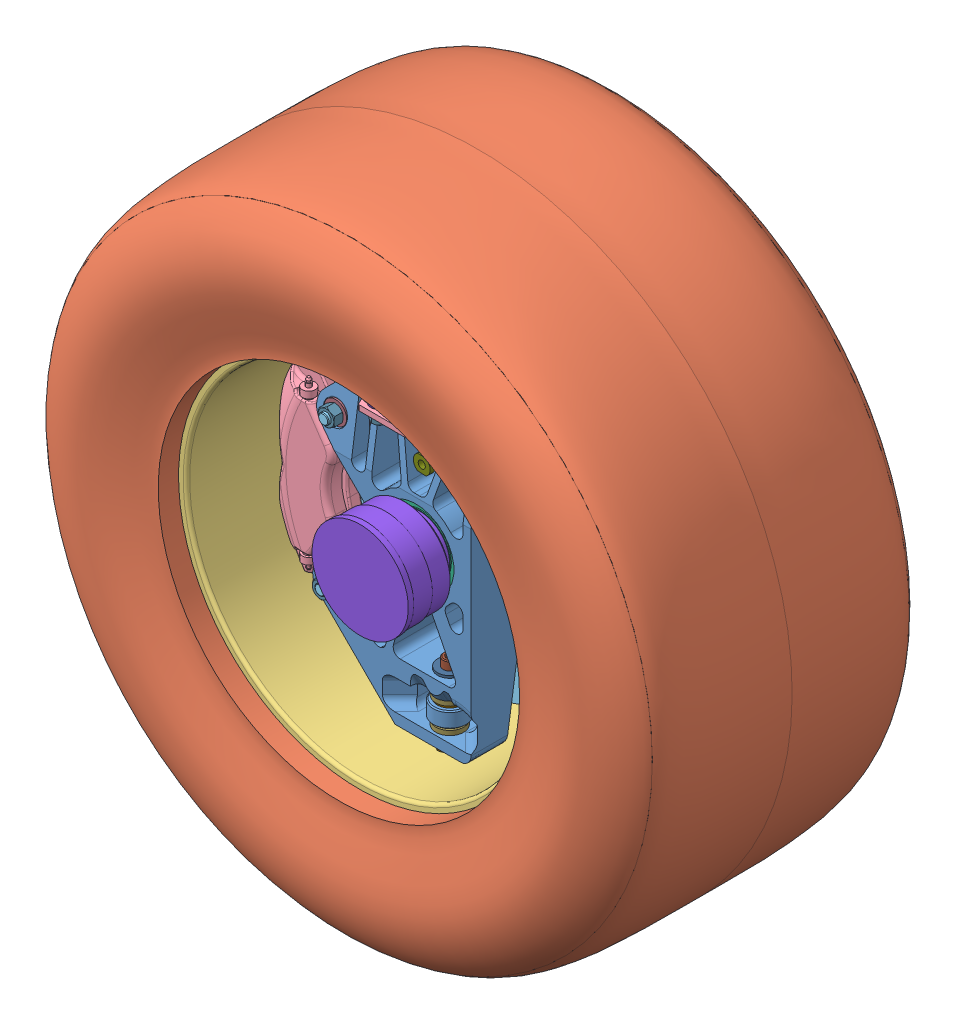
SolidWorks assembly CornerLR_Complete, configuration Default. Lengths in mm.
Overall size (801.05 801.05 310.41).
79 component instances, 32 part files, 138 mates.
Components (placement in the parent):
- UprighntLFLugBillet-2: UprighntLFLugBillet [Final Part] at origin size (558 599.44 88.5)
- TireRear-2: TireRear [Default] at (0 0 8.825) x (-0.562655 -0.826691 0) z (0 0 1) size (576.57 576.57 310.41)
- Wheel9J13-2: Wheel9J13 [Default] at (0 0 -6.73) x (-0.380341 0.924846 0) z (0 0 -1) size (367.66 367.66 243.31)
- SteeringArm-2: SteeringArm [Finished Part Left] at (-42.5 126.5 51.625) size (110 32.34 39)
- BrakeDiscWilwood160-10021-1: BrakeDiscWilwood160-10021 [Default] at (0 0 12.675) x (0.133038 0.991111 0) z (0 0 1) size (266.7 266.7 9.12)
- BearingWheelCivicFront-1: BearingWheelCivicFront [Default] at (0 0 21.82) x (-0.973136 -0.230231 0) z (0 0 1) size (73.1 73.1 55.34)
- WheelNut-1: WheelNut [Default] at (-0.0272 -0.0421 -52.1943) x (0 0 -1) z (0.976774 0.21427 0) size (26.97 65 74.13)
- WheelDrivePin-1: WheelDrivePin [Default] at (-44.0227 -18.1043 -6.38) x (-0.73494 0.678133 0) z (0.678133 0.73494 0) size (19.05 44.86 17)
- WheelDrivePin-2: WheelDrivePin [Default] at (44.0227 18.1043 -6.38) x (0.925266 0.379318 0) z (0.379318 -0.925266 0) size (19.05 44.86 17)
- WheelDrivePin-3: WheelDrivePin [Default] at (18.1043 -44.0227 -6.38) x (0.256263 -0.966607 0) z (-0.966607 -0.256263 0) size (19.05 44.86 17)
- WheelDrivePin-4: WheelDrivePin [Default] at (-18.1043 44.0227 -6.38) x (0.572125 0.820166 0) z (0.820166 -0.572125 0) size (19.05 44.86 17)
- Pin625-1: Pin625 [Default] at (15.843 -95 50.4139) x (-0.837169 0 -0.546944) z (0.546944 0 -0.837169) size (25.4 58 20)
- Flat Washer Type A Wide_AI-1: Flat Washer Type A Wide_AI [Preferred Wide FW 0.3125] at (15.843 -95 50.4139) x (0 -1 0) z (0.546944 0 -0.837169) size (2.11 22.23 22.23)
- Socket Head Cap Screw_AI-1: Socket Head Cap Screw_AI [HX-SHCS 0.3125-24x0.4375x0.4375-N] at (15.843 -84.9543 50.4139) x (0 -1 0) z (0.546944 0 -0.837169) size (19.05 11.91 11.91)
- Basic Internal Retaining Ring_am-1: Basic Internal Retaining Ring_am [B27.7M - 3BM1-72] at (0 0 21.667) x (0.982503 0.186249 0) z (0 0 1) size (76.5 74.92 2.4)
- Flat Washer Type A Narrow_AI-5: Flat Washer Type A Narrow_AI [Preferred Narrow FW 0.3125] at (-29.5 126.5 62.625) x (0 0 -1) z (0.926229 -0.376962 0) size (1.65 17.48 17.48)
- Flat Washer Type A Narrow_AI-6: Flat Washer Type A Narrow_AI [Preferred Narrow FW 0.3125] at (32.5 126.5 62.625) x (0 0 -1) z (0.352455 0.935829 0) size (1.65 17.48 17.48)
- Flat Washer Type A Narrow_AI-7: Flat Washer Type A Narrow_AI [Preferred Narrow FW 0.3125] at (32.5 126.5 40.625) x (0 0 1) z (-1 0 0) size (1.65 17.48 17.48)
- Flat Washer Type A Narrow_AI-8: Flat Washer Type A Narrow_AI [Preferred Narrow FW 0.3125] at (-29.5 126.5 40.625) x (0 0 1) z (-1 0 0) size (1.65 17.48 17.48)
- Socket Head Cap Screw_AI-2: Socket Head Cap Screw_AI [HX-SHCS 0.3125-24x1.25x1.25-N] at (-29.5 126.5 72.2135) x (0 0 -1) z (1 0 0) size (39.69 11.91 11.91)
- Socket Head Cap Screw_AI-3: Socket Head Cap Screw_AI [HX-SHCS 0.3125-24x1.25x1.25-N] at (32.5 126.5 72.2135) x (0 0 -1) z (1 0 0) size (39.69 11.91 11.91)
- Hex Nut_AI-7: Hex Nut_AI [HNUT 0.3125-24-D-N] at (32.5 126.5 32.0398) x (0.923728 0.383049 0) z (0 0 -1) size (12.7 14.66 6.93)
- Hex Nut_AI-8: Hex Nut_AI [HNUT 0.3125-24-D-N] at (-29.5 126.5 32.0398) x (0.923728 0.383049 0) z (0 0 -1) size (12.7 14.66 6.93)
- RodEnd8mmFem-2: RodEnd8mmFem [Default] at (59.9 121.5 82.525) x (-0.999058 0 -0.043388) z (0 -1 0) size (22 47 22.2) (flexible)
  - RodEndBall8mm-1: RodEndBall8mm [Default] at origin size (15.88 15.88 22.2)
  - RodEndRace8mmFem-1: RodEndRace8mmFem [Default] at origin size (22 47 14)
- bush437x500x345-1: bush437x500x345 [Default] at (-16.1 133.7499 82.525) x (0.999868 0 -0.016231) z (0.016231 0 0.999868) size (16 8.75 16)
- bush437x500x345-2: bush437x500x345 [Default] at (-16.1 119.2501 82.525) x (-0.439949 0 -0.898023) z (-0.898023 0 0.439949) size (16 8.75 16)
- BearingSpherical625-1: BearingSpherical625 [Default] at (15.843 -125.485 50.4139) x (0.913358 0 -0.407157) z (0.407157 0 0.913358) size (30.79 22.58 32.6) (flexible)
  - SphericalBearingBall625-1: SphericalBearingBall625 [Default] x (1 0 0) z (0 -1 0) size (26.97 32.6 22.58)
  - SphericalBeaingRace625-1: SphericalBeaingRace625 [Default] x (0.999776 0 -0.021151) z (0 -1 0) size (30.16 30.16 14.4)
- SphericalBearing437in-1: SphericalBearing437in [Default] at (-16.1 126.5 82.525) x (0.999488 0 -0.032002) z (0 -1 0) size (23.81 23.81 14.27) (flexible)
  - SphericalBearing437Race-1: SphericalBearing437Race [Default] at origin size (23.81 23.81 11.23)
  - SphericalBearing437Ball-1: SphericalBearing437Ball [Default] at origin size (19.84 19.84 14.27)
- CaliperWilwood120-6818-1: CaliperWilwood120-6818 [Default] at (-77.1694 0 31.975) x (0 1 0) z (0 0 1) size (180.93 86.45 102.63)
- Flat Washer Type A Narrow_AI-1: Flat Washer Type A Narrow_AI [Preferred Narrow FW 0.375] at (-77.1694 66.7 27.025) x (0 0 1) z (-1 0 0) size (1.65 20.62 20.62)
- Flat Washer Type A Narrow_AI-2: Flat Washer Type A Narrow_AI [Preferred Narrow FW 0.375] at (-77.1694 -66.7 27.025) x (0 0 1) z (-1 0 0) size (1.65 20.62 20.62)
- Flat Washer Type A Narrow_AI-3: Flat Washer Type A Narrow_AI [Preferred Narrow FW 0.375] at (-77.1694 -66.7 65.625) x (0 0 -1) z (1 0 0) size (1.65 20.62 20.62)
- Flat Washer Type A Narrow_AI-4: Flat Washer Type A Narrow_AI [Preferred Narrow FW 0.375] at (-77.1694 66.7 60.225) x (0 0 -1) z (1 0 0) size (1.65 20.62 20.62)
- Hex Bolt_AI-1: Hex Bolt_AI [HBOLT 0.375-24x1.875x1-N] at (-77.1694 66.7 18.5668) x (0 0 1) z (-1 0 0) size (54.43 16.48 14.27)
- Hex Bolt_AI-2: Hex Bolt_AI [HBOLT 0.375-24x2x1-N] at (-77.1694 -66.7 18.5668) x (0 0 1) z (-1 0 0) size (57.61 16.48 14.27)
- Hex Nut_AI-1: Hex Nut_AI [HNUT 0.3750-24-D-N] at (-77.1694 66.7 70.4358) size (14.27 16.48 8.56)
- Hex Nut_AI-2: Hex Nut_AI [HNUT 0.3750-24-D-N] at (-77.1694 -66.7 75.8358) x (0.99983 0.018462 0) z (0 0 1) size (14.27 16.48 8.56)
- WheelHubHondaCivic-1: WheelHubHondaCivic [Default] at (0 0 21.82) x (0.999997 -0.002534 0) z (0 0 -1) size (120.8 125.54 59.3)
- AdapterWheelHubToDisc-1: AdapterWheelHubToDisc [Finished Part] at (0 0 5.62) x (0.924846 0.380341 0) z (0 0 1) size (138.98 157.7 6)
- CVjointCivicOuter-1: CVjointCivicOuter [Default] at (0 0 116.42) x (0 0 -1) z (0.202887 0.979202 0) size (134.6 88 88)
- NutHondaCivWhlBrngRet-1: NutHondaCivWhlBrngRet [Default] at (0 0 -2.08) x (-0.872533 0.488555 0) z (0 0 -1) size (36.6 36.6 19.8)
- AxleStub-1: AxleStub [Default] at (0 0 3.92) x (0.822864 -0.568239 0) z (0 0 1) size (56.9 57.5 80.26)
- SpacerWheelHubToWheel-1: SpacerWheelHubToWheel [Default] at (0 0 -6.73) x (0.924846 0.380341 0) z (0 0 1) size (117.5 117.5 6.35)
- Bush16x19x4-1: Bush16x19x4 [Upper Bushing] at (15.843 -111.86 50.4139) x (-1 0 0) z (0 0 1) size (25.4 20.96 25.4)
- Bush16x19x4-2: Bush16x19x4 [Lower Bushing] at (15.843 -139.2 50.4139) x (0.837169 0 -0.546944) z (0.546944 0 0.837169) size (25.4 13.9 25.4)
- Flat Washer Type A Narrow_AI-29: Flat Washer Type A Narrow_AI [Preferred Narrow FW 0.3125] at (-16.1 142.5 82.525) x (0 -1 0) z (0 0 1) size (1.65 17.48 17.48)
- Flat Washer Type A Narrow_AI-30: Flat Washer Type A Narrow_AI [Preferred Narrow FW 0.3125] at (-16.1 110.5 82.525) x (0 1 0) z (0 0 1) size (1.65 17.48 17.48)
- Hex Nut_AI-22: Hex Nut_AI [HNUT 0.3125-24-D-N] at (-16.1 101.9148 82.525) x (1 0 0) z (0 -1 0) size (12.7 14.66 6.93)
- Flat Washer Type A Narrow_AI-31: Flat Washer Type A Narrow_AI [Preferred Narrow FW 0.3125] at (59.9 110.5 82.525) x (0 1 0) z (0 0 1) size (1.65 17.48 17.48)
- Flat Washer Type A Narrow_AI-32: Flat Washer Type A Narrow_AI [Preferred Narrow FW 0.3125] at (59.9 132.0562 82.525) x (0 -1 0) z (0 0 1) size (1.65 17.48 17.48)
- Hex Nut_AI-23: Hex Nut_AI [HNUT 0.3125-24-D-N] at (59.9 101.9148 82.525) x (1 0 0) z (0 -1 0) size (12.7 14.66 6.93)
- Hex Bolt_AI-9: Hex Bolt_AI [HBOLT 0.3125-24x1.75x1.75-N] at (-16.1 150.12 82.525) x (0 -1 0) z (0 0 1) size (50.42 14.66 12.7)
- Hex Bolt_AI-10: Hex Bolt_AI [HBOLT 0.3125-24x1.25x1.25-N] at (59.9 139.6763 82.525) x (0 -1 0) z (0 0 1) size (37.72 14.66 12.7)
- StudDiscMntRear-1: StudDiscMntRear [Default] at (69.2291 -9.2927 8.23) x (0 0 -1) z (1 0 0) size (26.61 16 18)
- StudDiscMntRear-2: StudDiscMntRear [Default] at (42.6623 55.3078 8.23) x (0 0 -1) z (0.5 0.866025 0) size (26.61 16 18)
- StudDiscMntRear-3: StudDiscMntRear [Default] at (-26.5669 64.6005 8.23) x (0 0 -1) z (-0.5 0.866025 0) size (26.61 16 18)
- StudDiscMntRear-4: StudDiscMntRear [Default] at (-69.2291 9.2927 8.23) x (0 0 -1) z (-1 0 0) size (26.61 16 18)
- StudDiscMntRear-5: StudDiscMntRear [Default] at (-42.6623 -55.3078 8.23) x (0 0 -1) z (-0.5 -0.866025 0) size (26.61 16 18)
- StudDiscMntRear-6: StudDiscMntRear [Default] at (26.5669 -64.6005 8.23) x (0 0 -1) z (0.5 -0.866025 0) size (26.61 16 18)
- Flat Washer Type A Narrow_AI-33: Flat Washer Type A Narrow_AI [Preferred Narrow FW 0.3125] at (69.2291 -9.2927 -0.38) x (0 0 1) z (-1 0 0) size (1.65 17.48 17.48)
- Hex Nut_AI-25: Hex Nut_AI [HNUT 0.3125-24-D-N] at (69.2291 -9.2927 -8.9652) x (0.923728 0.383049 0) z (0 0 -1) size (12.7 14.66 6.93)
- Hex Nut_AI-26: Hex Nut_AI [HNUT 0.3125-24-D-N] at (42.6623 55.3078 -8.9652) x (0.130134 0.991496 0) z (0 0 -1) size (12.7 14.66 6.93)
- Hex Nut_AI-27: Hex Nut_AI [HNUT 0.3125-24-D-N] at (-26.5669 64.6005 -8.9652) x (-0.793594 0.608447 0) z (0 0 -1) size (12.7 14.66 6.93)
- Hex Nut_AI-28: Hex Nut_AI [HNUT 0.3125-24-D-N] at (-69.2291 9.2927 -8.9652) x (-0.923728 -0.383049 0) z (0 0 -1) size (12.7 14.66 6.93)
- Hex Nut_AI-29: Hex Nut_AI [HNUT 0.3125-24-D-N] at (-42.6623 -55.3078 -8.9652) x (-0.130134 -0.991496 0) z (0 0 -1) size (12.7 14.66 6.93)
- Hex Nut_AI-30: Hex Nut_AI [HNUT 0.3125-24-D-N] at (26.5669 -64.6005 -8.9652) x (0.793594 -0.608447 0) z (0 0 -1) size (12.7 14.66 6.93)
- Flat Washer Type A Narrow_AI-34: Flat Washer Type A Narrow_AI [Preferred Narrow FW 0.3125] at (42.6623 55.3078 -0.38) x (0 0 1) z (-0.5 -0.866025 0) size (1.65 17.48 17.48)
- Flat Washer Type A Narrow_AI-35: Flat Washer Type A Narrow_AI [Preferred Narrow FW 0.3125] at (-26.5669 64.6005 -0.38) x (0 0 1) z (0.5 -0.866025 0) size (1.65 17.48 17.48)
- Flat Washer Type A Narrow_AI-36: Flat Washer Type A Narrow_AI [Preferred Narrow FW 0.3125] at (-69.2291 9.2927 -0.38) x (0 0 1) z (1 0 0) size (1.65 17.48 17.48)
- Flat Washer Type A Narrow_AI-37: Flat Washer Type A Narrow_AI [Preferred Narrow FW 0.3125] at (-42.6623 -55.3078 -0.38) x (0 0 1) z (0.5 0.866025 0) size (1.65 17.48 17.48)
- Flat Washer Type A Narrow_AI-38: Flat Washer Type A Narrow_AI [Preferred Narrow FW 0.3125] at (26.5669 -64.6005 -0.38) x (0 0 1) z (-0.5 0.866025 0) size (1.65 17.48 17.48)
- SpacerSteeringArm3mm-5: SpacerSteeringArm3mm [Default] at (32.5 126.5 48.625) x (-1 0 0) z (0 0 1) size (26 32 3)
- SpacerSteeringArm3mm-6: SpacerSteeringArm3mm [Default] at (-29.5 126.5 48.625) size (26 32 3)
Mates (geometry in assembly coordinates):
- Concentric241: concentric: cylinder of assembly; cylinder of assembly; cylinder of Pin625-1 through (15.843 -149 50.4139) axis (0 1 0) radius 7.9375; cylinder of UprighntLFLugBillet-2 through (15.843 -149 50.4139) axis (0 1 0) radius 9.525
- Coincident211: coincident: plane of assembly; plane of assembly; plane of UprighntLFLugBillet-2 through (-99.5 -149 15.625) normal (0 -1 0); plane of Pin625-1 through (15.843 -149 50.4139) normal (0 1 0)
- Concentric251: concentric: cylinder of Flat Washer Type A Wide_AI-1 through (15.843 -60.075 50.4139) axis (0 1 0) radius 4.7625; cylinder of Pin625-1 through (15.843 -149 50.4139) axis (0 1 0) radius 7.9375
- Coincident221: coincident: plane of Pin625-1 through (15.843 -95 50.4139) normal (0 1 0); plane of Flat Washer Type A Wide_AI-1 through (11.856 -95 47.8091) normal (0 -1 0)
- Concentric261: concentric: cylinder of Flat Washer Type A Wide_AI-1 through (15.843 -60.075 50.4139) axis (0 1 0) radius 11.1125; cylinder of Socket Head Cap Screw_AI-1 through (15.843 -53.2043 50.4139) axis (0 1 0) radius 5.9538
- Coincident231: coincident: plane of Flat Washer Type A Wide_AI-1 through (6.54 -92.8918 44.336) normal (0 1 0); plane of Socket Head Cap Screw_AI-1 through (10.8587 -92.8918 47.1575) normal (0 -1 0)
- Concentric2621: concentric: cylinder of assembly; cylinder of assembly; cylinder of Basic Internal Retaining Ring_am-1 through (0 0 19.267) axis (0 0 1) radius 38.25; cylinder of UprighntLFLugBillet-2 through (0 0 61.82) axis (0 0 -1) radius 36.5
- Concentric26221: concentric: cylinder of assembly; cylinder of assembly; cylinder of SteeringArm-2 through (-29.5 126.5 93.625) axis (0 0 -1) radius 4.1021; cylinder of Flat Washer Type A Narrow_AI-5 through (-29.5 126.5 97.55) axis (0 0 1) radius 4.3688
- Coincident2321: coincident: plane of assembly; plane of SteeringArm-2 through (12.8365 126.7309 62.625) normal (0 0 1); plane of Flat Washer Type A Narrow_AI-5 through (-27.8531 130.5465 62.625) normal (0 0 -1)
- Concentric26231: concentric: cylinder of assembly; cylinder of assembly; cylinder of SteeringArm-2 through (32.5 126.5 93.625) axis (0 0 -1) radius 4.1021; cylinder of Flat Washer Type A Narrow_AI-6 through (32.5 126.5 97.55) axis (0 0 1) radius 4.3688
- Coincident2331: coincident: plane of assembly; plane of assembly; plane of SteeringArm-2 through (12.8365 126.7309 62.625) normal (0 0 1); plane of Flat Washer Type A Narrow_AI-6 through (28.4116 128.0398 62.625) normal (0 0 -1)
- Concentric26241: concentric: cylinder of assembly; cylinder of assembly; cylinder of Flat Washer Type A Narrow_AI-7 through (32.5 126.5 5.7) axis (0 0 -1) radius 4.3688; cylinder of Socket Head Cap Screw_AI-3 through (32.5 126.5 103.9635) axis (0 0 1) radius 3.9688
- Coincident2341: coincident: plane of assembly; plane of assembly; plane of UprighntLFLugBillet-2 through (38.5625 118.4375 40.625) normal (0 0 -1); plane of Flat Washer Type A Narrow_AI-7 through (32.5 130.8688 40.625) normal (0 0 1)
- Concentric26251: concentric: cylinder of assembly; cylinder of assembly; cylinder of Flat Washer Type A Narrow_AI-8 through (-29.5 126.5 5.7) axis (0 0 -1) radius 4.3688; cylinder of Socket Head Cap Screw_AI-2 through (-29.5 126.5 103.9635) axis (0 0 1) radius 3.9688
- Coincident2351: coincident: plane of assembly; plane of assembly; plane of UprighntLFLugBillet-2 through (38.5625 118.4375 40.625) normal (0 0 -1); plane of Flat Washer Type A Narrow_AI-8 through (-29.5 130.8688 40.625) normal (0 0 1)
- Concentric26261: concentric: cylinder of assembly; cylinder of assembly; cylinder of SteeringArm-2 through (-29.5 126.5 93.625) axis (0 0 -1) radius 4.1021; cylinder of Socket Head Cap Screw_AI-2 through (-29.5 126.5 103.9635) axis (0 0 1) radius 5.9538
- Coincident2361: coincident: plane of assembly; plane of assembly; plane of Flat Washer Type A Narrow_AI-5 through (-26.2063 134.593 64.276) normal (0 0 1); plane of Socket Head Cap Screw_AI-2 through (-29.5 132.4538 64.276) normal (0 0 -1)
- Concentric26281: concentric: cylinder of assembly; cylinder of assembly; cylinder of SteeringArm-2 through (32.5 126.5 93.625) axis (0 0 -1) radius 4.1021; cylinder of Socket Head Cap Screw_AI-3 through (32.5 126.5 103.9635) axis (0 0 1) radius 5.9538
- Coincident2381: coincident: plane of assembly; plane of assembly; plane of Flat Washer Type A Narrow_AI-6 through (24.3231 129.5796 64.276) normal (0 0 1); plane of Socket Head Cap Screw_AI-3 through (32.5 132.4538 64.276) normal (0 0 -1)
- Concentric26291: concentric: cylinder of assembly; cylinder of assembly; cylinder of Flat Washer Type A Narrow_AI-7 through (32.5 126.5 5.7) axis (0 0 -1) radius 4.3688; cylinder of Hex Nut_AI-7 through (32.5 126.5 57.0773) axis (0 0 -1) radius 3.9688
- Coincident2391: coincident: plane of assembly; plane of assembly; plane of Flat Washer Type A Narrow_AI-7 through (32.5 135.2376 38.974) normal (0 0 -1); plane of Hex Nut_AI-7 through (35.3086 119.7269 38.974) normal (0 0 1)
- Concentric26301: concentric: cylinder of assembly; cylinder of assembly; cylinder of Flat Washer Type A Narrow_AI-8 through (-29.5 126.5 5.7) axis (0 0 -1) radius 4.3688; cylinder of Hex Nut_AI-8 through (-29.5 126.5 57.0773) axis (0 0 -1) radius 3.9688
- Coincident2401: coincident: plane of assembly; plane of assembly; plane of Flat Washer Type A Narrow_AI-8 through (-29.5 135.2376 38.974) normal (0 0 -1); plane of Hex Nut_AI-8 through (-26.6914 119.7269 38.974) normal (0 0 1)
- Coincident241: coincident: plane of assembly; plane of assembly; plane of UprighntLFLugBillet-2 through (34.0068 0 19.267) normal (0 0 1); plane of Basic Internal Retaining Ring_am-1 through (0 0 19.267) normal (0 0 -1)
- Concentric2632: concentric: cylinder of assembly; cylinder of assembly; cylinder of SteeringArm-2 through (-29.5 126.5 93.625) axis (0 0 -1) radius 4.1021; cylinder of UprighntLFLugBillet-2 through (-29.5 126.5 65.625) axis (0 0 -1) radius 4.1021
- Concentric2635: concentric: cylinder of SteeringArm-2 through (59.9 110.5 82.525) axis (0 1 0) radius 4.1021; cylinder of ? through (59.9 90.241 82.525) axis (0 -1 0) radius 4
- Coincident244: coincident: point of SteeringArm-2; point of RodEnd8mmFem-2/RodEndBall8mm-1
- Concentric2636: concentric: cylinder of assembly; cylinder of assembly; cylinder of SteeringArm-2 through (-16.1 110.5 82.525) axis (0 1 0) radius 6.35; cylinder of bush437x500x345-1 through (-16.1 137.6125 82.525) axis (0 -1 0) radius 5.5563
- Concentric2637: concentric: cylinder of assembly; cylinder of assembly; cylinder of SteeringArm-2 through (-16.1 110.5 82.525) axis (0 1 0) radius 6.35; cylinder of bush437x500x345-2 through (-16.1 115.3875 82.525) axis (0 1 0) radius 5.5563
- Coincident245: coincident: plane of assembly; plane of assembly; plane of SteeringArm-2 through (-42.5 137.6125 129.625) normal (0 -1 0); plane of bush437x500x345-1 through (-16.1 137.6125 82.525) normal (0 1 0)
- Coincident246: coincident: plane of assembly; plane of assembly; plane of SteeringArm-2 through (-42.5 115.3875 129.625) normal (0 1 0); plane of bush437x500x345-2 through (-16.1 115.3875 82.525) normal (0 -1 0)
- Distance1: distance = 6 mm: plane of assembly; plane of assembly; plane of UprighntLFLugBillet-2 through (38.5625 118.4375 48.625) normal (0 0 1); plane of SteeringArm-2 through (-42.5 142.5 54.625) normal (0 0 -1)
- Concentric26303: concentric: cylinder of assembly; cylinder of assembly; cylinder of Pin625-1 through (15.843 -149 50.4139) axis (0 1 0) radius 7.9375; cylinder of BearingSpherical625-1/SphericalBearingBall625-1 through (15.843 -115.5936 50.4139) axis (0 1 0) radius 7.94
- Coincident2402: coincident: plane of assembly; plane of assembly; plane of BearingSpherical625-1/SphericalBearingBall625-1 through (19.0758 -115.96 57.6659) normal (0 1 0); plane of Bush16x19x4-1 through (3.143 -115.96 50.4139) normal (0 -1 0)
- Concentric26310: concentric: cylinder of SteeringArm-2 through (-16.1 110.5 82.525) axis (0 1 0) radius 6.35; cylinder of ? through (-16.1 132.1134 82.525) axis (0 -1 0) radius 11.9062
- Concentric26311: concentric: sphere of SteeringArm-2; unknown of ?
- Distance4: distance = 102 mm: line of CaliperWilwood120-6818-1 through (-77.1694 66.7 31.975) axis (0 0 1); line of BearingWheelCivicFront-1 through (0 0 13.2488) axis (0 0 1)
- Distance5: distance = 102 mm: line of CaliperWilwood120-6818-1 through (-77.1694 -66.7 49.225) axis (0 0 -1); line of BearingWheelCivicFront-1 through (0 0 13.2488) axis (0 0 1)
- Parallel1: parallel: plane of assembly through (0 0 0) normal (0 0 1); plane of CaliperWilwood120-6818-1 through (-77.1694 0 31.975) normal (0 0 1); plane of assembly
- Distance6: distance = 19.3 mm: plane of assembly; plane of assembly; plane of BrakeDiscWilwood160-10021-1 through (0 0 12.675) normal (0 0 1); plane of CaliperWilwood120-6818-1 through (-77.1694 -66.7 31.975) normal (0 0 -1)
- Parallel2: parallel: plane of assembly through (0 0 0) normal (1 0 0); plane of CaliperWilwood120-6818-1 through (-77.1694 0 31.975) normal (-1 0 0); plane of assembly
- Concentric263402: concentric: cylinder of Flat Washer Type A Narrow_AI-1 through (-77.1694 66.7 -7.9) axis (0 0 -1) radius 5.1562; cylinder of Hex Bolt_AI-1 through (-77.1694 66.7 18.5668) axis (0 0 -1) radius 4.7625
- Coincident24383: coincident: plane of UprighntLFLugBillet-2 through (-77.191 66.675 27.025) normal (0 0 -1); plane of Flat Washer Type A Narrow_AI-1 through (-77.1694 71.8562 27.025) normal (0 0 1)
- Concentric263403: concentric: cylinder of Flat Washer Type A Narrow_AI-2 through (-77.1694 -66.7 -7.9) axis (0 0 -1) radius 5.1562; cylinder of Hex Bolt_AI-2 through (-77.1694 -66.7 18.5668) axis (0 0 -1) radius 4.7625
- Coincident24384: coincident: plane of UprighntLFLugBillet-2 through (-77.191 -66.675 27.025) normal (0 0 -1); plane of Flat Washer Type A Narrow_AI-2 through (-77.1694 -61.5438 27.025) normal (0 0 1)
- Coincident24385: coincident: plane of UprighntLFLugBillet-2 through (0 0 65.625) normal (0 0 1); plane of Flat Washer Type A Narrow_AI-3 through (-77.1694 -61.5438 65.625) normal (0 0 -1)
- Concentric263405: concentric: cylinder of Flat Washer Type A Narrow_AI-4 through (-77.1694 66.7 95.15) axis (0 0 1) radius 5.1562; cylinder of Hex Bolt_AI-1 through (-77.1694 66.7 18.5668) axis (0 0 -1) radius 4.7625
- Coincident24386: coincident: plane of UprighntLFLugBillet-2 through (-77.191 66.675 60.225) normal (0 0 1); plane of Flat Washer Type A Narrow_AI-4 through (-77.1694 71.8562 60.225) normal (0 0 -1)
- Coincident24387: coincident: plane of Flat Washer Type A Narrow_AI-1 through (-77.1694 77.0124 25.374) normal (0 0 -1); plane of Hex Bolt_AI-1 through (-77.1694 74.9416 25.374) normal (0 0 1)
- Coincident24388: coincident: plane of Flat Washer Type A Narrow_AI-2 through (-77.1694 -56.3876 25.374) normal (0 0 -1); plane of Hex Bolt_AI-2 through (-77.1694 -58.4584 25.374) normal (0 0 1)
- Concentric263408: concentric: cylinder of Hex Bolt_AI-1 through (-77.1694 66.7 18.5668) axis (0 0 -1) radius 4.7625; cylinder of Hex Nut_AI-1 through (-77.1694 66.7 45.3983) axis (0 0 1) radius 4.7625
- Coincident24389: coincident: plane of Flat Washer Type A Narrow_AI-4 through (-77.1694 77.0124 61.876) normal (0 0 1); plane of Hex Nut_AI-1 through (-91.4442 66.7 61.876) normal (0 0 -1)
- Concentric263409: concentric: cylinder of Hex Bolt_AI-2 through (-77.1694 -66.7 18.5668) axis (0 0 -1) radius 4.7625; cylinder of Hex Nut_AI-2 through (-77.1694 -66.7 50.7983) axis (0 0 1) radius 4.7625
- Coincident24390: coincident: plane of Flat Washer Type A Narrow_AI-3 through (-77.1694 -56.3876 67.276) normal (0 0 1); plane of Hex Nut_AI-2 through (-91.4417 -66.9635 67.276) normal (0 0 -1)
- Coincident24406: coincident: plane of assembly; plane of assembly; plane of Pin625-1 through (15.843 -149 50.4139) normal (0 1 0); plane of UprighntLFLugBillet-2 through (-99.5 -149 15.625) normal (0 -1 0)
- Concentric263423: concentric: cylinder of assembly; cylinder of assembly; cylinder of SteeringArm-2 through (-29.5 126.5 93.625) axis (0 0 1) radius 4.1021; cylinder of Flat Washer Type A Narrow_AI-5 through (-29.5 126.5 97.55) axis (0 0 1) radius 4.3688
- Coincident24409: coincident: plane of ? through (12.8365 126.7309 -60.2175) normal (0 0 -1); plane of Flat Washer Type A Narrow_AI-5 through (-27.8531 130.5465 62.625) normal (0 0 -1)
- Concentric263424: concentric: cylinder of assembly; cylinder of assembly; cylinder of SteeringArm-2 through (32.5 126.5 93.625) axis (0 0 -1) radius 4.1021; cylinder of Flat Washer Type A Narrow_AI-6 through (32.5 126.5 97.55) axis (0 0 1) radius 4.3688
- Coincident24410: coincident: plane of ? through (12.8365 126.7309 -60.2175) normal (0 0 -1); plane of Flat Washer Type A Narrow_AI-6 through (28.4116 128.0398 62.625) normal (0 0 -1)
- Concentric263425: concentric: cylinder of assembly; cylinder of assembly; cylinder of Flat Washer Type A Narrow_AI-7 through (32.5 126.5 5.7) axis (0 0 -1) radius 4.3688; cylinder of Socket Head Cap Screw_AI-3 through (32.5 126.5 103.9635) axis (0 0 1) radius 5.9538
- Coincident24411: coincident: plane of assembly; plane of assembly; plane of UprighntLFLugBillet-2 through (38.5625 118.4375 40.625) normal (0 0 -1); plane of Flat Washer Type A Narrow_AI-7 through (32.5 130.8688 40.625) normal (0 0 1)
- Concentric263427: concentric: cylinder of assembly; cylinder of assembly; cylinder of SteeringArm-2 through (-29.5 126.5 93.625) axis (0 0 1) radius 4.1021; cylinder of Socket Head Cap Screw_AI-2 through (-29.5 126.5 103.9635) axis (0 0 1) radius 5.9538
- Coincident24413: coincident: plane of assembly; plane of assembly; plane of Flat Washer Type A Narrow_AI-5 through (-26.2063 134.593 64.276) normal (0 0 1); plane of Socket Head Cap Screw_AI-2 through (-29.5 132.4538 64.276) normal (0 0 -1)
- Concentric263428: concentric: cylinder of assembly; cylinder of assembly; cylinder of SteeringArm-2 through (32.5 126.5 93.625) axis (0 0 -1) radius 4.1021; cylinder of Socket Head Cap Screw_AI-3 through (32.5 126.5 103.9635) axis (0 0 1) radius 5.9538
- Coincident24414: coincident: plane of assembly; plane of assembly; plane of Flat Washer Type A Narrow_AI-6 through (24.3231 129.5796 64.276) normal (0 0 1); plane of Socket Head Cap Screw_AI-3 through (32.5 132.4538 64.276) normal (0 0 -1)
- Coincident24415: coincident: plane of assembly; plane of assembly; plane of Flat Washer Type A Narrow_AI-7 through (32.5 135.2376 38.974) normal (0 0 -1); plane of Hex Nut_AI-7 through (35.3086 119.7269 32.0398) normal (0 0 -1)
- Concentric263430: concentric: cylinder of assembly; cylinder of assembly; cylinder of SteeringArm-2 through (32.5 126.5 93.625) axis (0 0 -1) radius 4.1021; cylinder of UprighntLFLugBillet-2 through (32.5 126.5 65.625) axis (0 0 -1) radius 4.1021
- Concentric263431: concentric: cylinder of assembly; cylinder of assembly; cylinder of SteeringArm-2 through (-16.1 110.5 82.525) axis (0 1 0) radius 6.35; cylinder of bush437x500x345-1 through (-16.1 137.6125 82.525) axis (0 -1 0) radius 5.5563
- Concentric263432: concentric: cylinder of assembly; cylinder of assembly; cylinder of SteeringArm-2 through (-16.1 110.5 82.525) axis (0 1 0) radius 6.35; cylinder of bush437x500x345-2 through (-16.1 115.3875 82.525) axis (0 1 0) radius 5.5563
- Coincident24418: coincident: plane of assembly; plane of assembly; plane of SteeringArm-2 through (-42.5 137.6125 129.625) normal (0 -1 0); plane of bush437x500x345-1 through (-16.1 137.6125 82.525) normal (0 1 0)
- Coincident24419: coincident: plane of ? through (-42.5 115.5 -129.2175) normal (0 1 0); plane of bush437x500x345-2 through (-16.1 119.2501 82.525) normal (0 1 0)
- Concentric263470: concentric: cylinder of assembly; cylinder of assembly; cylinder of BearingWheelCivicFront-1 through (0 0 61.82) axis (0 0 -1) radius 19; cylinder of WheelHubHondaCivic-1 through (0 0 21.82) axis (0 0 1) radius 19
- Concentric263471: concentric: cylinder of assembly; cylinder of assembly; cylinder of UprighntLFLugBillet-2 through (0 0 61.82) axis (0 0 -1) radius 36.5; cylinder of BearingWheelCivicFront-1 through (0 0 61.82) axis (0 0 -1) radius 36.55
- Coincident24471: coincident: plane of assembly; plane of assembly; plane of UprighntLFLugBillet-2 through (0 0 61.82) normal (0 0 -1); plane of BearingWheelCivicFront-1 through (0 0 61.82) normal (0 0 1)
- Coincident24472: coincident: plane of assembly; plane of assembly; plane of UprighntLFLugBillet-2 through (-94.191 13.875 49.225) normal (0 0 -1); plane of CaliperWilwood120-6818-1 through (-77.1694 -66.7 49.225) normal (0 0 1)
- Coincident24473: coincident: plane of assembly; plane of assembly; plane of BearingWheelCivicFront-1 through (0 0 21.82) normal (0 0 -1); plane of WheelHubHondaCivic-1 through (-0.0494 -19.4999 21.82) normal (0 0 1)
- Coincident24474: coincident: plane of assembly; plane of assembly; plane of WheelHubHondaCivic-1 through (-0.153 -60.3998 5.62) normal (0 0 -1); plane of AdapterWheelHubToDisc-1 through (-11.5624 28.1153 5.62) normal (0 0 1)
- Concentric263474: concentric: cylinder of assembly; cylinder of assembly; cylinder of WheelHubHondaCivic-1 through (0 0 21.82) axis (0 0 1) radius 14.1; cylinder of CVjointCivicOuter-1 through (0 0 276.1473) axis (0 0 1) radius 13.5
- Coincident24476: coincident: plane of assembly; plane of assembly; plane of BearingWheelCivicFront-1 through (0 0 61.82) normal (0 0 1); plane of CVjointCivicOuter-1 through (-13.2192 2.739 61.82) normal (0 0 -1)
- Concentric263480: concentric: cylinder of assembly; cylinder of assembly; cylinder of CVjointCivicOuter-1 through (0 0 276.1473) axis (0 0 1) radius 11; cylinder of NutHondaCivWhlBrngRet-1 through (0 0 -29.8385) axis (0 0 -1) radius 10.2
- Concentric263481: concentric: cylinder of assembly; cylinder of assembly; cylinder of CVjointCivicOuter-1 through (0 0 276.1473) axis (0 0 1) radius 11; cylinder of AxleStub-1 through (0 0 50.1767) axis (0 0 1) radius 10.9
- Coincident24479: coincident: plane of assembly; plane of assembly; plane of NutHondaCivWhlBrngRet-1 through (4.9833 8.8998 -2.08) normal (0 0 1); plane of AxleStub-1 through (9.7453 14.1121 -2.08) normal (0 0 -1)
- Coincident24480: coincident: plane of assembly; plane of assembly; plane of WheelHubHondaCivic-1 through (-0.0355 -14 3.92) normal (0 0 -1); plane of AxleStub-1 through (10.967 15.8813 3.92) normal (0 0 1)
- Coincident24481: coincident: plane of assembly; plane of assembly; plane of WheelDrivePin-3 through (15.6633 -34.8157 -0.38) normal (0 0 1); plane of AdapterWheelHubToDisc-1 through (-22.3451 54.3347 -0.38) normal (0 0 -1)
- Concentric263483: concentric: cylinder of assembly; cylinder of WheelDrivePin-3 through (18.1043 -44.0227 65.6665) axis (0 0 1) radius 9.525; cylinder of AdapterWheelHubToDisc-1 through (18.1043 -44.0227 -0.38) axis (0 0 1) radius 6.5481
- Concentric263484: concentric: cylinder of assembly; cylinder of assembly; cylinder of WheelDrivePin-2 through (44.0227 18.1043 65.6665) axis (0 0 1) radius 6.35; cylinder of WheelHubHondaCivic-1 through (44.0227 18.1043 5.62) axis (0 0 -1) radius 5.7544
- Coincident24482: coincident: plane of assembly; plane of assembly; plane of WheelDrivePin-2 through (35.2095 14.4912 -0.38) normal (0 0 1); plane of AdapterWheelHubToDisc-1 through (-22.3451 54.3347 -0.38) normal (0 0 -1)
- Concentric263486: concentric: cylinder of assembly; cylinder of assembly; cylinder of WheelDrivePin-4 through (-18.1043 44.0227 65.6665) axis (0 0 1) radius 6.35; cylinder of WheelHubHondaCivic-1 through (-18.1043 44.0227 5.62) axis (0 0 -1) radius 5.7544
- Coincident24483: coincident: plane of assembly; plane of assembly; plane of WheelDrivePin-4 through (-23.5537 36.2106 -0.38) normal (0 0 1); plane of AdapterWheelHubToDisc-1 through (-22.3451 54.3347 -0.38) normal (0 0 -1)
- Coincident24484: coincident: plane of assembly; plane of assembly; plane of WheelDrivePin-1 through (-37.0224 -24.5635 -0.38) normal (0 0 1); plane of AdapterWheelHubToDisc-1 through (-22.3451 54.3347 -0.38) normal (0 0 -1)
- Concentric263510: concentric: cylinder of assembly; cylinder of assembly; cylinder of Wheel9J13-2 through (0 0 -139.9944) axis (0 0 -1) radius 30; cylinder of AxleStub-1 through (0 0 50.1767) axis (0 0 1) radius 27.85
- Coincident24504: coincident: plane of assembly; plane of assembly; plane of Wheel9J13-2 through (27.7454 11.4102 -6.73) normal (0 0 1); plane of SpacerWheelHubToWheel-1 through (0 0 -6.73) normal (0 0 -1)
- Concentric263511: concentric: cylinder of assembly; cylinder of assembly; cylinder of Wheel9J13-2 through (-44.0227 -18.1043 -31.73) axis (0 0 1) radius 4.75; cylinder of WheelDrivePin-1 through (-44.0227 -18.1043 65.6665) axis (0 0 1) radius 6.6675
- Concentric263512: concentric: cylinder of assembly; cylinder of assembly; cylinder of WheelDrivePin-1 through (-44.0227 -18.1043 65.6665) axis (0 0 1) radius 6.35; cylinder of WheelHubHondaCivic-1 through (-44.0227 -18.1043 5.62) axis (0 0 -1) radius 5.7544
- Concentric263513: concentric: cylinder of assembly; cylinder of assembly; cylinder of WheelDrivePin-3 through (18.1043 -44.0227 65.6665) axis (0 0 1) radius 6.35; cylinder of WheelHubHondaCivic-1 through (18.1043 -44.0227 5.62) axis (0 0 -1) radius 5.7544
- Concentric263514: concentric: cylinder of assembly; cylinder of assembly; cylinder of AxleStub-1 through (0 0 50.1767) axis (0 0 1) radius 27.85; cylinder of SpacerWheelHubToWheel-1 through (0 0 -0.38) axis (0 0 -1) radius 34.5
- Coincident24505: coincident: plane of assembly; plane of assembly; plane of AdapterWheelHubToDisc-1 through (-22.3451 54.3347 -0.38) normal (0 0 -1); plane of SpacerWheelHubToWheel-1 through (0 0 -0.38) normal (0 0 1)
- Concentric263515: concentric: cylinder of assembly; cylinder of assembly; cylinder of AdapterWheelHubToDisc-1 through (18.1043 -44.0227 -0.38) axis (0 0 1) radius 6.5481; cylinder of SpacerWheelHubToWheel-1 through (18.1043 -44.0227 -0.38) axis (0 0 -1) radius 9.55
- Concentric263516: concentric: cylinder of assembly; cylinder of assembly; cylinder of Pin625-1 through (15.843 -149 50.4139) axis (0 1 0) radius 7.9375; cylinder of Bush16x19x4-1 through (15.843 -147.6258 50.4139) axis (0 -1 0) radius 7.9375
- Coincident24506: coincident: plane of assembly; plane of assembly; plane of UprighntLFLugBillet-2 through (-8.5 -111.86 15.625) normal (0 -1 0); plane of Bush16x19x4-1 through (6.318 -111.86 50.4139) normal (0 1 0)
- Concentric263517: concentric: cylinder of assembly; cylinder of assembly; cylinder of Pin625-1 through (15.843 -149 50.4139) axis (0 1 0) radius 7.9375; cylinder of Bush16x19x4-2 through (15.843 -103.4342 50.4139) axis (0 1 0) radius 7.9375
- Coincident24507: coincident: plane of assembly; plane of assembly; plane of UprighntLFLugBillet-2 through (-8.5 -139.2 15.625) normal (0 1 0); plane of Bush16x19x4-2 through (23.8171 -139.2 45.2042) normal (0 -1 0)
- Concentric263518: concentric: cylinder of assembly; cylinder of assembly; cylinder of SteeringArm-2 through (-16.1 110.5 82.525) axis (0 1 0) radius 6.35; cylinder of Flat Washer Type A Narrow_AI-29 through (-16.1 177.425 82.525) axis (0 1 0) radius 4.3688
- Coincident24508: coincident: plane of assembly; plane of assembly; plane of SteeringArm-2 through (-42.5 142.5 129.625) normal (0 1 0); plane of Flat Washer Type A Narrow_AI-29 through (-11.7312 142.5 82.525) normal (0 -1 0)
- Concentric263519: concentric: cylinder of assembly; cylinder of assembly; cylinder of SteeringArm-2 through (-16.1 110.5 82.525) axis (0 1 0) radius 6.35; cylinder of Flat Washer Type A Narrow_AI-30 through (-16.1 75.575 82.525) axis (0 -1 0) radius 4.3688
- Coincident24509: coincident: plane of assembly; plane of assembly; plane of SteeringArm-2 through (-42.5 110.5 129.625) normal (0 -1 0); plane of Flat Washer Type A Narrow_AI-30 through (-20.4688 110.5 82.525) normal (0 1 0)
- Concentric263520: concentric: cylinder of assembly; cylinder of assembly; cylinder of Flat Washer Type A Narrow_AI-30 through (-16.1 75.575 82.525) axis (0 -1 0) radius 4.3688; cylinder of Hex Nut_AI-22 through (-16.1 126.9523 82.525) axis (0 -1 0) radius 3.9688
- Coincident24510: coincident: plane of assembly; plane of assembly; plane of Flat Washer Type A Narrow_AI-30 through (-24.8376 108.849 82.525) normal (0 -1 0); plane of Hex Nut_AI-22 through (-16.1 108.849 89.8573) normal (0 1 0)
- Concentric263521: concentric: cylinder of assembly; cylinder of assembly; cylinder of SteeringArm-2 through (59.9 110.5 82.525) axis (0 1 0) radius 4.1021; cylinder of Flat Washer Type A Narrow_AI-31 through (59.9 75.575 82.525) axis (0 -1 0) radius 4.3688
- Coincident24511: coincident: plane of assembly; plane of assembly; plane of SteeringArm-2 through (-42.5 110.5 129.625) normal (0 -1 0); plane of Flat Washer Type A Narrow_AI-31 through (55.5312 110.5 82.525) normal (0 1 0)
- Concentric263522: concentric: cylinder of assembly; cylinder of assembly; cylinder of SteeringArm-2 through (59.9 110.5 82.525) axis (0 1 0) radius 4.1021; cylinder of Flat Washer Type A Narrow_AI-32 through (59.9 166.9812 82.525) axis (0 1 0) radius 4.3688
- Coincident24512: coincident: plane of assembly; plane of assembly; plane of SteeringArm-2 through (52.5 132.0562 129.625) normal (0 1 0); plane of Flat Washer Type A Narrow_AI-32 through (64.2688 132.0562 82.525) normal (0 -1 0)
- Concentric263523: concentric: cylinder of assembly; cylinder of assembly; cylinder of Flat Washer Type A Narrow_AI-31 through (59.9 75.575 82.525) axis (0 -1 0) radius 4.3688; cylinder of Hex Nut_AI-23 through (59.9 126.9523 82.525) axis (0 -1 0) radius 3.9688
- Coincident24513: coincident: plane of assembly; plane of assembly; plane of Flat Washer Type A Narrow_AI-31 through (51.1624 108.849 82.525) normal (0 -1 0); plane of Hex Nut_AI-23 through (59.9 108.849 89.8573) normal (0 1 0)
- Concentric263524: concentric: cylinder of assembly; cylinder of assembly; cylinder of SteeringArm-2 through (-16.1 110.5 82.525) axis (0 1 0) radius 6.35; cylinder of Hex Bolt_AI-9 through (-16.1 150.12 82.525) axis (0 1 0) radius 3.9688
- Coincident24514: coincident: plane of assembly; plane of assembly; plane of Flat Washer Type A Narrow_AI-29 through (-7.3624 144.151 82.525) normal (0 1 0); plane of Hex Bolt_AI-9 through (-8.7677 144.151 82.525) normal (0 -1 0)
- Concentric263525: concentric: cylinder of assembly; cylinder of assembly; cylinder of SteeringArm-2 through (59.9 110.5 82.525) axis (0 1 0) radius 4.1021; cylinder of Hex Bolt_AI-10 through (59.9 139.6763 82.525) axis (0 1 0) radius 3.9688
- Coincident24515: coincident: plane of assembly; plane of assembly; plane of Flat Washer Type A Narrow_AI-32 through (68.6376 133.7072 82.525) normal (0 1 0); plane of Hex Bolt_AI-10 through (67.2323 133.7072 82.525) normal (0 -1 0)
- Concentric263526: concentric: cylinder of CaliperWilwood120-6818-1 through (-77.1694 66.7 49.225) axis (0 0 -1) radius 4.95; cylinder of Hex Bolt_AI-1 through (-77.1694 66.7 18.5668) axis (0 0 -1) radius 4.7625
- Concentric263527: concentric: cylinder of Flat Washer Type A Narrow_AI-3 through (-77.1694 -66.7 100.55) axis (0 0 1) radius 5.1562; cylinder of Hex Bolt_AI-2 through (-77.1694 -66.7 18.5668) axis (0 0 -1) radius 4.7625
- Concentric263528: concentric: cylinder of CaliperWilwood120-6818-1 through (-77.1694 -66.7 49.225) axis (0 0 -1) radius 4.95; cylinder of Hex Bolt_AI-2 through (-77.1694 -66.7 18.5668) axis (0 0 -1) radius 4.7625
- Concentric263529: concentric: cylinder of assembly; cylinder of assembly; cylinder of TireRear-2 through (0 0 -186.0725) axis (0 0 -1) radius 165; cylinder of Wheel9J13-2 through (0 0 -139.9944) axis (0 0 -1) radius 165
- Coincident24521: coincident: circle of assembly; cone of assembly; circle of TireRear-2; cone of Wheel9J13-2 through (0 0 -118.2415) axis (0 0 1)
- Concentric263530: concentric: cylinder of assembly; cylinder of assembly; cylinder of BrakeDiscWilwood160-10021-1 through (69.2291 -9.2927 8.23) axis (0 0 1) radius 4; cylinder of StudDiscMntRear-1 through (69.2291 -9.2927 46.404) axis (0 0 1) radius 4
- Concentric263532: concentric: cylinder of assembly; cylinder of assembly; cylinder of BrakeDiscWilwood160-10021-1 through (69.2291 -9.2927 8.23) axis (0 0 1) radius 4; cylinder of AdapterWheelHubToDisc-1 through (69.2291 -9.2927 -0.38) axis (0 0 1) radius 4.1021
- Coincident24523: coincident: plane of assembly; plane of assembly; plane of BrakeDiscWilwood160-10021-1 through (0 0 8.23) normal (0 0 -1); plane of StudDiscMntRear-1 through (69.2291 -5.2927 8.23) normal (0 0 1)
- Concentric263533: concentric: cylinder of assembly; cylinder of assembly; cylinder of AdapterWheelHubToDisc-1 through (69.2291 -9.2927 -0.38) axis (0 0 1) radius 4.1021; cylinder of Flat Washer Type A Narrow_AI-33 through (69.2291 -9.2927 -35.305) axis (0 0 -1) radius 4.3688
- Coincident24524: coincident: plane of assembly; plane of assembly; plane of AdapterWheelHubToDisc-1 through (-22.3451 54.3347 -0.38) normal (0 0 -1); plane of Flat Washer Type A Narrow_AI-33 through (69.2291 -4.9239 -0.38) normal (0 0 1)
- Concentric263535: concentric: cylinder of assembly; cylinder of assembly; cylinder of Flat Washer Type A Narrow_AI-33 through (69.2291 -9.2927 -35.305) axis (0 0 -1) radius 4.3688; cylinder of Hex Nut_AI-25 through (69.2291 -9.2927 16.0723) axis (0 0 -1) radius 3.9688
- Coincident24525: coincident: plane of assembly; plane of assembly; plane of Flat Washer Type A Narrow_AI-33 through (69.2291 -0.5551 -2.031) normal (0 0 -1); plane of Hex Nut_AI-25 through (72.0378 -16.0658 -2.031) normal (0 0 1)
- Concentric263536: concentric: cylinder of assembly; cylinder of assembly; cylinder of Socket Head Cap Screw_AI-3 through (32.5 126.5 103.9635) axis (0 0 1) radius 5.9538; cylinder of SpacerSteeringArm3mm-5 through (32.5 126.5 51.625) axis (0 0 -1) radius 4.1021
- Coincident24529: coincident: plane of assembly; plane of assembly; plane of UprighntLFLugBillet-2 through (38.5625 118.4375 48.625) normal (0 0 1); plane of SpacerSteeringArm3mm-5 through (17.5 142.5 48.625) normal (0 0 -1)
- Concentric263537: concentric: cylinder of assembly; cylinder of assembly; cylinder of Socket Head Cap Screw_AI-2 through (-29.5 126.5 103.9635) axis (0 0 1) radius 5.9538; cylinder of SpacerSteeringArm3mm-6 through (-29.5 126.5 51.625) axis (0 0 -1) radius 4.1021
- Coincident24531: coincident: plane of assembly; plane of assembly; plane of UprighntLFLugBillet-2 through (38.5625 118.4375 48.625) normal (0 0 1); plane of SpacerSteeringArm3mm-6 through (-14.5 110.5 48.625) normal (0 0 -1)
- Perpendicular3: perpendicular: plane of assembly; plane of assembly; plane of SteeringArm-2 through (-42.5 126.5 51.625) normal (0 1 0); plane of SpacerSteeringArm3mm-5 through (32.5 126.5 48.625) normal (-1 0 0)
- Perpendicular2: perpendicular: plane of assembly; plane of assembly; plane of SteeringArm-2 through (-42.5 126.5 51.625) normal (0 1 0); plane of SpacerSteeringArm3mm-6 through (-29.5 126.5 48.625) normal (1 0 0)
- Concentric263538: concentric: cylinder of assembly; cylinder of WheelHubHondaCivic-1 through (0 0 21.82) axis (0 0 1) radius 60.4; circle of AdapterWheelHubToDisc-1
- Concentric263539: concentric: cylinder of assembly; cylinder of BrakeDiscWilwood160-10021-1 through (0 0 8.23) axis (0 0 1) radius 62.738; circle of AdapterWheelHubToDisc-1
